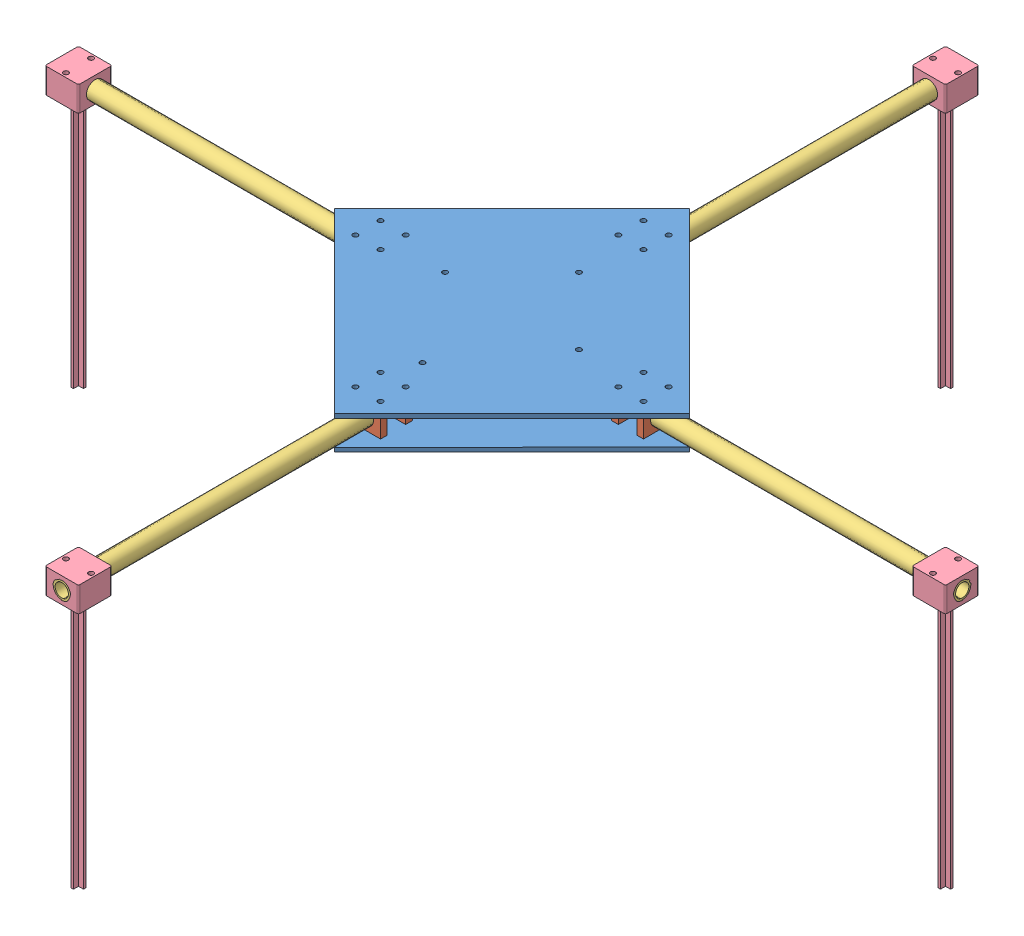
SolidWorks assembly new_drone_full_body_landing, configuration Default. Lengths in mm.
Overall size (538.13 167.5 538.13).
18 component instances, 4 part files, 81 mates.
Components (placement in the parent):
- base-plate_drone_new-1: base-plate_drone_new [Default] at (-94378.7064 -1163.9739 82221.6136) size (212.13 2.5 212.15)
- holder-1: holder [Default] at (71.6083 102.2761 266.6718) x (1 0 0) z (0 1 0) size (19 4 15)
- holder-2: holder [Default] at (71.5935 87.2761 247.6718) x (1 0 0) z (0 -1 0) size (19 4 15)
- holder-4: holder [Default] at (12.0275 87.2761 169.1058) x (0 0 1) z (0 -1 0) size (19 4 15)
- holder-6: holder [Default] at (-6.9728 87.2761 188.1203) x (0.00014 0 -1) z (0 -1 0) size (19 4 15)
- holder-7: holder [Default] at (90.5787 102.2761 90.5398) x (-1 0 0) z (0 1 0) size (19 4 15)
- holder-8: holder [Default] at (71.5935 87.2761 105.5398) x (1 0 0) z (0 -1 0) size (19 4 15)
- holder-9: holder [Default] at (165.1595 102.2761 169.091) x (0 0 1) z (0 1 0) size (19 4 15)
- holder-10: holder [Default] at (150.1595 87.2761 188.1058) x (0 0 -1) z (0 -1 0) size (19 4 15)
- New_arm-1: New_arm [Default] at (350.1595 94.7761 178.6058) x (0 0 1) z (1 0 0) size (10.5 10.5 200)
- New_arm-2: New_arm [Default] at (81.0935 94.7761 109.5398) size (10.5 10.5 200)
- New_arm-3: New_arm [Default] at (12.0275 94.7761 178.6058) x (0 0.007654 -0.999971) z (1 0 0) size (10.5 10.5 200)
- New_arm-4: New_arm [Default] at (81.0935 94.7761 447.6718) size (10.5 10.5 200)
- base-plate_drone_new-2: base-plate_drone_new [Default] at (-94378.7064 -1146.4739 82221.6136) size (212.13 2.5 212.15)
- motormount-1: motormount [Default] at (81.0935 94.7761 -90.4602) x (1 0 0) z (0 -1 0) size (20 20 165)
- motormount-2: motormount [Default] at (-187.9725 94.7761 178.6058) x (0 0 -1) z (0 -1 0) size (20 20 165)
- motormount-3: motormount [Default] at (81.0935 94.7761 427.6718) x (1 0 0) z (0 -1 0) size (20 20 165)
- motormount-4: motormount [Default] at (330.1595 94.7761 178.6058) x (0 0 -1) z (0 -1 0) size (20 20 165)
Mates (geometry in assembly coordinates):
- Coincident6: coincident: circle of base-plate_drone_new-1; circle of holder-1
- Concentric1: concentric: circle of base-plate_drone_new-1; circle of holder-1
- Coincident8: coincident: circle of base-plate_drone_new-1; circle of holder-2
- Coincident9: coincident: circle of base-plate_drone_new-1; circle of holder-2
- Coincident16: coincident: circle of base-plate_drone_new-1; circle of holder-4
- Coincident17: coincident: circle of base-plate_drone_new-1; circle of holder-4
- Coincident20: coincident: circle of base-plate_drone_new-1; circle of holder-6
- Parallel2: parallel: cylinder of base-plate_drone_new-1 through (-4.9725 87.2761 171.1058) axis (0 -1 0) radius 1.5; cylinder of holder-6 through (-4.9704 102.2761 171.1206) axis (0 -1 0) radius 1.5
- Coincident22: coincident: circle of base-plate_drone_new-1; circle of holder-7
- Parallel3: parallel: cylinder of base-plate_drone_new-1 through (88.5935 87.2761 92.5398) axis (0 -1 0) radius 1.5; cylinder of holder-7 through (88.5787 87.2761 92.5398) axis (0 1 0) radius 1.5
- Coincident24: coincident: circle of base-plate_drone_new-1; circle of holder-8
- Coincident25: coincident: circle of base-plate_drone_new-1; circle of holder-8
- Coincident27: coincident: circle of base-plate_drone_new-1; circle of holder-9
- Parallel5: parallel: cylinder of base-plate_drone_new-1 through (167.1595 87.2761 186.1058) axis (0 -1 0) radius 1.5; cylinder of holder-9 through (167.1595 87.2761 186.091) axis (0 1 0) radius 1.5
- Coincident28: coincident: circle of base-plate_drone_new-1; circle of holder-10
- Coincident29: coincident: circle of base-plate_drone_new-1; circle of holder-10
- Concentric11: concentric: cylinder of holder-4 through (8.0275 94.7761 178.6058) axis (1 0 0) radius 5.25; cylinder of New_arm-3 through (-187.9725 94.7761 178.6058) axis (1 0 0) radius 5.25
- Coincident30: coincident: plane of holder-4 through (12.0275 87.2761 169.1058) normal (1 0 0); plane of New_arm-3 through (12.0275 94.7761 178.6058) normal (1 0 0)
- Concentric12: concentric: cylinder of holder-8 through (81.0935 94.7761 109.5398) axis (0 0 -1) radius 5.25; cylinder of New_arm-2 through (81.0935 94.7761 -90.4602) axis (0 0 1) radius 5.25
- Coincident31: coincident: plane of holder-8 through (71.5935 87.2761 109.5398) normal (0 0 1); plane of New_arm-2 through (81.0935 94.7761 109.5398) normal (0 0 1)
- Concentric13: concentric: cylinder of holder-2 through (81.0935 94.7761 251.6718) axis (0 0 -1) radius 5.25; cylinder of New_arm-4 through (81.0935 94.7761 247.6718) axis (0 0 1) radius 5.25
- Coincident32: coincident: plane of holder-2 through (71.5935 87.2761 247.6718) normal (0 0 -1); plane of New_arm-4 through (81.0935 94.7761 247.6718) normal (0 0 -1)
- Concentric14: concentric: cylinder of holder-10 through (154.1595 94.7761 178.6058) axis (-1 0 0) radius 5.25; cylinder of New_arm-1 through (150.1595 94.7761 178.6058) axis (1 0 0) radius 5.25
- Coincident33: coincident: plane of holder-10 through (150.1595 87.2761 188.1058) normal (-1 0 0); plane of New_arm-1 through (150.1595 94.7761 178.6058) normal (-1 0 0)
- Coincident34: coincident: circle of holder-7; circle of base-plate_drone_new-2
- Parallel6: parallel: cylinder of holder-7 through (88.5787 87.2761 92.5398) axis (0 1 0) radius 1.5; cylinder of base-plate_drone_new-2 through (88.5935 104.7761 92.5398) axis (0 -1 0) radius 1.5
- Coincident36: coincident: circle of holder-8; circle of base-plate_drone_new-2
- Parallel7: parallel: cylinder of holder-8 through (73.5935 102.2761 107.5398) axis (0 -1 0) radius 1.5; cylinder of base-plate_drone_new-2 through (73.5935 104.7761 107.5398) axis (0 -1 0) radius 1.5
- Coincident37: coincident: circle of holder-8; circle of base-plate_drone_new-2
- Parallel8: parallel: cylinder of holder-9 through (167.1595 87.2761 186.091) axis (0 1 0) radius 1.5; cylinder of base-plate_drone_new-2 through (167.1595 104.7761 186.1058) axis (0 -1 0) radius 1.5
- Parallel9: parallel: cylinder of holder-9 through (167.1595 87.2761 171.091) axis (0 1 0) radius 1.5; cylinder of base-plate_drone_new-2 through (167.1595 104.7761 171.091) axis (0 -1 0) radius 1.5
- Parallel10: parallel: cylinder of holder-10 through (152.1595 102.2761 171.1058) axis (0 -1 0) radius 1.5; cylinder of base-plate_drone_new-2 through (152.1595 104.7761 171.1058) axis (0 -1 0) radius 1.5
- Parallel11: parallel: cylinder of holder-10 through (152.1595 102.2761 186.1058) axis (0 -1 0) radius 1.5; cylinder of base-plate_drone_new-2 through (152.1595 104.7761 186.1058) axis (0 -1 0) radius 1.5
- Parallel12: parallel: cylinder of holder-1 through (88.6083 87.2761 264.6718) axis (0 1 0) radius 1.5; cylinder of base-plate_drone_new-2 through (88.6083 104.7761 264.6718) axis (0 -1 0) radius 1.5
- Parallel13: parallel: cylinder of holder-2 through (88.5935 102.2761 249.6718) axis (0 -1 0) radius 1.5; cylinder of base-plate_drone_new-2 through (88.5935 104.7761 249.6718) axis (0 -1 0) radius 1.5
- Parallel14: parallel: cylinder of holder-2 through (73.5935 102.2761 249.6718) axis (0 -1 0) radius 1.5; cylinder of base-plate_drone_new-2 through (73.5935 104.7761 249.6718) axis (0 -1 0) radius 1.5
- Parallel15: parallel: cylinder of holder-1 through (73.6083 87.2761 264.6718) axis (0 1 0) radius 1.5; cylinder of base-plate_drone_new-2 through (73.5935 104.7761 264.6718) axis (0 -1 0) radius 1.5
- Coincident40: coincident: circle of holder-4; circle of base-plate_drone_new-2
- Coincident42: coincident: circle of holder-6; circle of base-plate_drone_new-2
- Parallel19: parallel: cylinder of holder-6 through (-4.9704 102.2761 171.1206) axis (0 -1 0) radius 1.5; cylinder of base-plate_drone_new-2 through (-4.9725 104.7761 171.1058) axis (0 -1 0) radius 1.5
- Lock1: lock: unknown of holder-6; unknown of base-plate_drone_new-2
- Lock2: lock: unknown of holder-4; unknown of base-plate_drone_new-2
- Lock3: lock: unknown of holder-4; unknown of base-plate_drone_new-2
- Lock4: lock: unknown of holder-6; unknown of base-plate_drone_new-2
- Lock5: lock: unknown of holder-7; unknown of base-plate_drone_new-2
- Lock6: lock: unknown of holder-7; unknown of base-plate_drone_new-2
- Lock7: lock: unknown of holder-8; unknown of base-plate_drone_new-2
- Lock8: lock: unknown of holder-8; unknown of base-plate_drone_new-2
- Lock9: lock: unknown of base-plate_drone_new-1; unknown of holder-8
- Lock10: lock: unknown of holder-9; unknown of base-plate_drone_new-2
- Lock11: lock: unknown of base-plate_drone_new-1; unknown of holder-9
- Lock12: lock: unknown of holder-10; unknown of base-plate_drone_new-2
- Lock13: lock: unknown of base-plate_drone_new-1; unknown of holder-10
- Lock14: lock: unknown of holder-10; unknown of base-plate_drone_new-2
- Lock15: lock: unknown of base-plate_drone_new-1; unknown of holder-10
- Lock16: lock: unknown of holder-9; unknown of base-plate_drone_new-2
- Lock17: lock: unknown of base-plate_drone_new-1; unknown of holder-9
- Lock18: lock: unknown of holder-2; unknown of base-plate_drone_new-2
- Lock19: lock: unknown of base-plate_drone_new-1; unknown of holder-2
- Lock20: lock: unknown of holder-1; unknown of base-plate_drone_new-2
- Lock21: lock: unknown of base-plate_drone_new-1; unknown of holder-1
- Lock22: lock: unknown of holder-1; unknown of base-plate_drone_new-2
- Lock23: lock: unknown of base-plate_drone_new-1; unknown of holder-1
- Lock24: lock: unknown of holder-2; unknown of base-plate_drone_new-2
- Lock25: lock: unknown of base-plate_drone_new-1; unknown of holder-2
- Lock26: lock: unknown of holder-8; unknown of New_arm-2
- Lock27: lock: unknown of holder-4; unknown of New_arm-3
- Lock28: lock: unknown of holder-2; unknown of New_arm-4
- Lock29: lock: unknown of holder-10; unknown of New_arm-1
- Concentric15: concentric: cylinder of New_arm-2 through (81.0935 94.7761 -90.4602) axis (0 0 1) radius 5.25; cylinder of motormount-1 through (81.0935 94.7761 -70.4602) axis (0 0 -1) radius 5
- Coincident43: coincident: plane of New_arm-2 through (81.0935 94.7761 -90.4602) normal (0 0 -1); plane of motormount-1 through (81.0935 94.7761 -90.4602) normal (0 0 -1)
- Concentric17: concentric: cylinder of New_arm-4 through (81.0935 94.7761 247.6718) axis (0 0 1) radius 5.25; cylinder of motormount-3 through (81.0935 94.7761 447.6718) axis (0 0 -1) radius 5
- Coincident44: coincident: plane of New_arm-4 through (81.0935 94.7761 447.6718) normal (0 0 1); plane of motormount-3 through (81.0935 94.7761 447.6718) normal (0 0 1)
- Parallel20: parallel: plane of base-plate_drone_new-2 through (-13.3786 104.7761 260.6495) normal (0 1 0); plane of motormount-3 through (71.0935 102.2761 447.6718) normal (0 1 0)
- Parallel21: parallel: plane of base-plate_drone_new-2 through (-13.3786 104.7761 260.6495) normal (0 1 0); plane of motormount-1 through (71.0935 102.2761 -70.4602) normal (0 1 0)
- Concentric18: concentric: cylinder of New_arm-3 through (-187.9725 94.7761 178.6058) axis (1 0 0) radius 5.25; cylinder of motormount-2 through (-167.9725 94.7761 178.6058) axis (-1 0 0) radius 5
- Coincident47: coincident: plane of New_arm-3 through (-187.9725 94.7761 178.6058) normal (-1 0 0); plane of motormount-2 through (-187.9725 94.7761 178.6058) normal (-1 0 0)
- Parallel23: parallel: plane of base-plate_drone_new-2 through (-13.3786 104.7761 260.6495) normal (0 1 0); plane of motormount-2 through (-167.9725 87.2761 188.6058) normal (0 -1 0)
- Concentric19: concentric: cylinder of New_arm-1 through (150.1595 94.7761 178.6058) axis (1 0 0) radius 5.25; cylinder of motormount-4 through (350.1595 94.7761 178.6058) axis (-1 0 0) radius 5
- Coincident50: coincident: plane of New_arm-1 through (350.1595 94.7761 178.6058) normal (1 0 0); plane of motormount-4 through (350.1595 94.7761 178.6058) normal (1 0 0)
- Parallel25: parallel: plane of base-plate_drone_new-2 through (-13.3786 104.7761 260.6495) normal (0 1 0); plane of motormount-4 through (350.1595 87.2761 188.6058) normal (0 -1 0)
